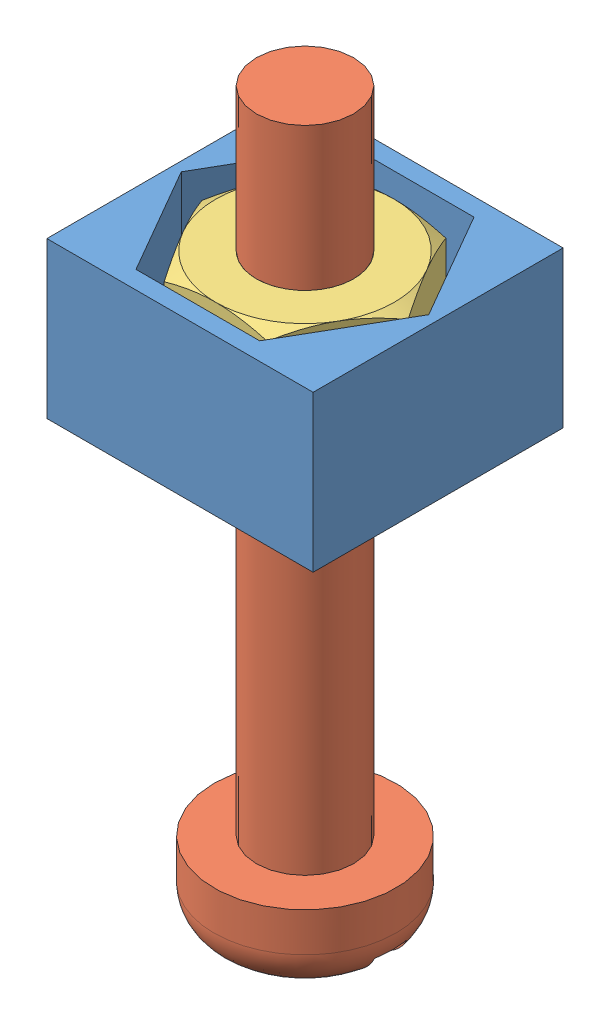
SolidWorks assembly nut_fastener, configuration Défaut. Lengths in mm.
Overall size (8.2 22.48 7.7).
3 component instances, 3 part files, 5 mates.
Components (placement in the parent):
- nut-1: nut [Défaut] at origin size (8.2 4.8 7.7)
- pan slot head_am (threaded)-1: pan slot head_am (threaded) [B18.6.7M - M3 x 0.5 x 20 Slotted PHMS --20N] at (0 -13.4 0) x (0 1 0) z (-1 0 0) size (22.48 5.6 5.6)
- hex nut style 1_am-2: hex nut style 1_am [B18.2.4.1M - Hex nut, Style 1,  M3 x 0.5 --D-N] at (0 4.6 0) x (0 0 1) z (0 1 0) size (5.5 6.35 2.4)
Mates (geometry in assembly coordinates):
- Coaxiale3: concentric anti-aligned: cylinder of nut-1 through (0 2.2 0) axis (0 -1 0) radius 1.5; cylinder of hex nut style 1_am-2 through (0 -20.4375 0) axis (0 1 0) radius 1.5
- Coïncidente116: coincident anti-aligned: plane of nut-1 through (0 2.2 0) normal (0 1 0); plane of hex nut style 1_am-2 through (3.1754 2.2 0) normal (0 -1 0)
- Parallèle3: parallel anti-aligned: plane of nut-1 through (2.8579 4.8 -1.65) normal (-0.866025 0 0.5); plane of hex nut style 1_am-2 through (3.1754 2.2 0) normal (0.866025 0 -0.5)
- Distance1: distance = 11 mm anti-aligned: plane of nut-1 through (0 0 0) normal (0 -1 0); plane of pan slot head_am (threaded)-1 through (0 -11 -1.5) normal (0 1 0)
- Coaxiale5: concentric aligned: cylinder of nut-1 through (0 2.2 0) axis (0 -1 0) radius 1.5; cylinder of pan slot head_am (threaded)-1 through (0 -38.8 0) axis (0 -1 0) radius 1.5
